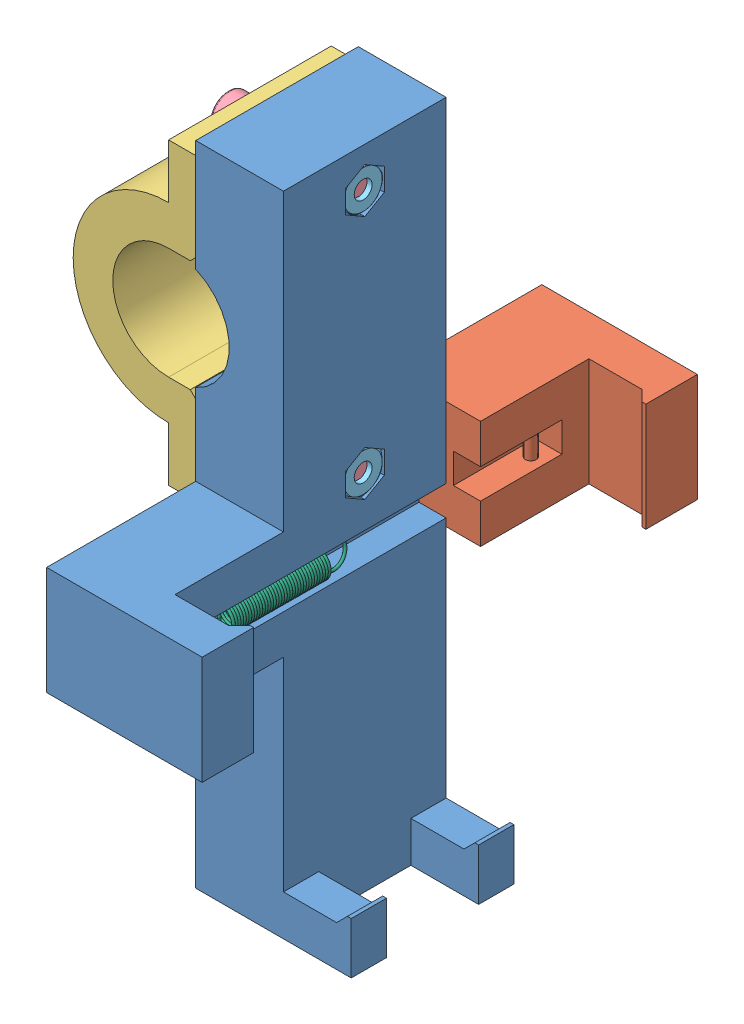
SolidWorks assembly assemblage, configuration Défaut. Lengths in mm.
Overall size (51.29 119.44 91.35).
8 component instances, 6 part files, 15 mates.
Components (placement in the parent):
- supportPrincipal-1: supportPrincipal [Défaut] at (-17.1177 24.6397 119.4443) size (28.69 119.44 57.5)
- bras_mobile-1: bras_mobile [Défaut] at (-13.0073 -20.3046 113.0924) x (0 0 -1) z (0 -1 0) size (47.5 28.69 20)
- attache-1: attache [Défaut] at (-18.0073 24.6397 119.4443) x (0 1 0) z (0 0 1) size (55.2 22.6 30)
- Vis à tête cylindrique à six pans creux Chc M4 - 20-1: Vis à tête cylindrique à six pans creux Chc M4 - 20 [Défaut] at (-18.0073 47.2397 134.4443) x (0 0 -1) z (1 0 0) size (7 7 24)
- Ecrou M4-1: Ecrou M4 [Défaut] at (2.8823 47.2397 134.4443) x (0 0.451623 0.892209) z (1 0 0) size (7 8.08 3.2)
- Vis à tête cylindrique à six pans creux Chc M4 - 20-2: Vis à tête cylindrique à six pans creux Chc M4 - 20 [Défaut] at (-18.0073 2.0397 134.4443) x (0 0 -1) z (1 0 0) size (7 7 24)
- Ecrou M4-2: Ecrou M4 [Défaut] at (2.8823 2.0397 134.4443) x (0 0 -1) z (1 0 0) size (7 8.08 3.2)
- Ressort-1: Ressort [Défaut] at (0.9304 -9.8445 140.9512) x (-0.000033 -0.003935 -0.999992) z (0.987938 0.154851 -0.000642) size (28.7 6.45 6.45)
Mates (geometry in assembly coordinates):
- Coïncidente1: coincident anti-aligned: plane of supportPrincipal-1 through (-13.0073 34.0839 149.4443) normal (-1 0 0); plane of attache-1 through (-13.0073 34.9397 149.4443) normal (1 0 0)
- Coaxiale1: concentric aligned: cylinder of supportPrincipal-1 through (16.9927 47.2397 134.4443) axis (-1 0 0) radius 2.6; cylinder of attache-1 through (-13.0073 47.2397 134.4443) axis (-1 0 0) radius 2.6
- Coaxiale2: concentric aligned: cylinder of supportPrincipal-1 through (16.9927 2.0397 134.4443) axis (-1 0 0) radius 2.6; cylinder of attache-1 through (-13.0073 2.0397 134.4443) axis (-1 0 0) radius 2.6
- Coïncidente6: coincident anti-aligned: plane of supportPrincipal-1 through (-10.0073 -11.5546 144.4443) normal (0 1 0); plane of bras_mobile-1 through (-5.5073 -11.5546 133.0924) normal (0 -1 0)
- Coïncidente8: coincident aligned: plane of supportPrincipal-1 through (-13.0073 15.1954 149.4443) normal (-1 0 0); plane of bras_mobile-1 through (-13.0073 -20.3046 113.0924) normal (-1 0 0)
- Coaxiale9: concentric anti-aligned: cylinder of supportPrincipal-1 through (16.9927 47.2397 134.4443) axis (-1 0 0) radius 2.6; cylinder of Vis à tête cylindrique à six pans creux Chc M4 - 20-1 through (-18.0073 47.2397 134.4443) axis (1 0 0) radius 2
- Coïncidente15: coincident anti-aligned: plane of attache-1 through (-18.0073 42.2397 149.4443) normal (-1 0 0); plane of Vis à tête cylindrique à six pans creux Chc M4 - 20-1 through (-18.0073 47.2397 134.4443) normal (1 0 0)
- Coaxiale10: concentric anti-aligned: cylinder of Vis à tête cylindrique à six pans creux Chc M4 - 20-1 through (-18.0073 47.2397 134.4443) axis (1 0 0) radius 2; cylinder of Ecrou M4-1 through (-0.3177 47.2397 134.4443) axis (-1 0 0) radius 1.65
- Coïncidente16: coincident anti-aligned: plane of supportPrincipal-1 through (-0.3177 24.6397 119.4443) normal (1 0 0); plane of Ecrou M4-1 through (-0.3177 40.2503 134.0594) normal (-1 0 0)
- Coïncidente17: coincident anti-aligned: plane of attache-1 through (-18.0073 -2.9603 149.4443) normal (-1 0 0); plane of Vis à tête cylindrique à six pans creux Chc M4 - 20-2 through (-18.0073 2.0397 134.4443) normal (1 0 0)
- Coaxiale11: concentric anti-aligned: cylinder of supportPrincipal-1 through (16.9927 2.0397 134.4443) axis (-1 0 0) radius 2.6; cylinder of Vis à tête cylindrique à six pans creux Chc M4 - 20-2 through (-18.0073 2.0397 134.4443) axis (1 0 0) radius 2
- Coïncidente18: coincident anti-aligned: plane of supportPrincipal-1 through (-0.3177 24.6397 119.4443) normal (1 0 0); plane of Ecrou M4-2 through (-0.3177 8.1018 137.9443) normal (-1 0 0)
- Coaxiale12: concentric anti-aligned: cylinder of Vis à tête cylindrique à six pans creux Chc M4 - 20-2 through (-18.0073 2.0397 134.4443) axis (1 0 0) radius 2; cylinder of Ecrou M4-2 through (-0.3177 2.0397 134.4443) axis (-1 0 0) radius 1.65
- Tangent3: tangent anti-aligned: plane of supportPrincipal-1 through (-1.8177 24.6397 119.4443) normal (1 0 0); face of Ressort-1
- Tangent4: tangent anti-aligned: plane of supportPrincipal-1 through (-1.8177 -7.0546 119.4443) normal (0 -1 0); edge_curve of Ressort-1
